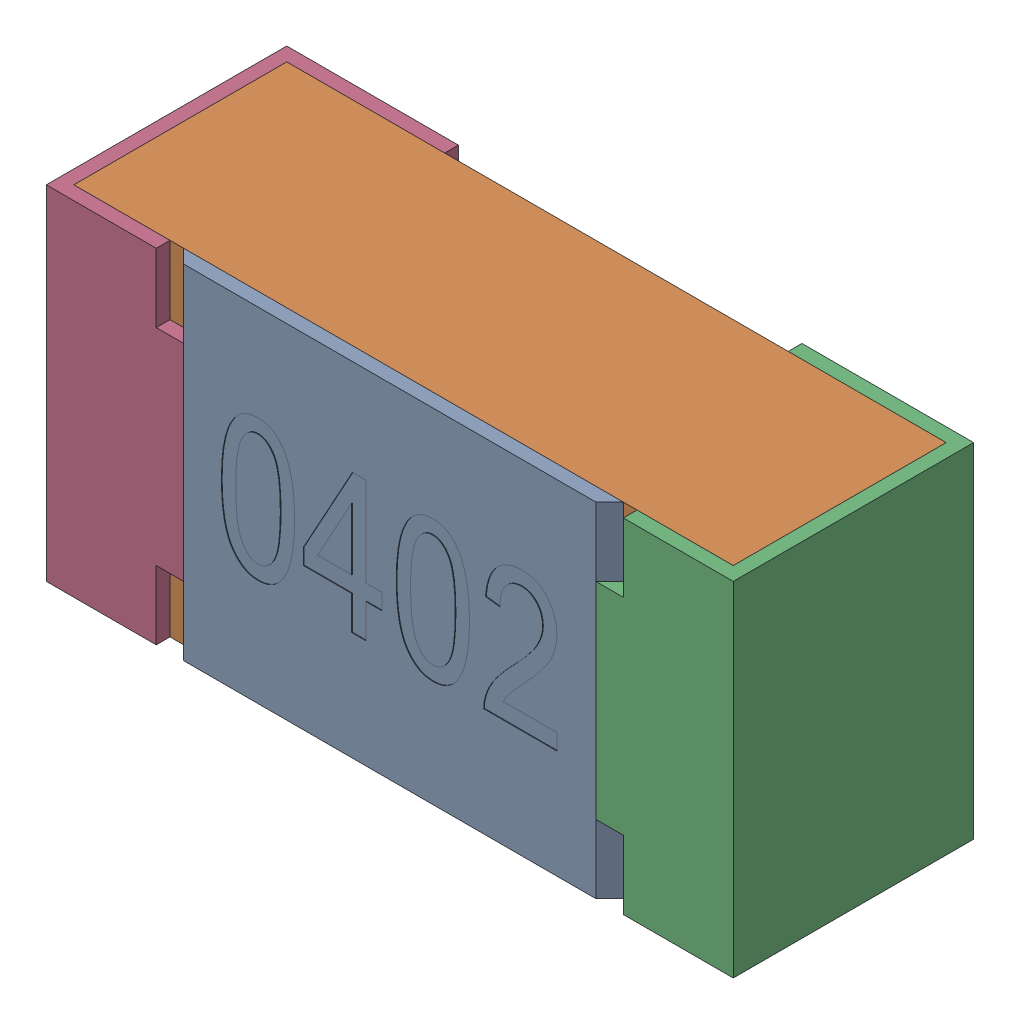
SolidWorks assembly R8, configuration Standard. Lengths in mm.
Overall size (1 0.5 0.35).
5 component instances, 4 part files, 0 mates.
Components (placement in the parent):
- R8-subassembly-1-1: R8-subassembly-1 [Standard] at (4.4001 -15.8 0) size (1 0.5 0.35)
  - User Library-R_0402-1: User Library-R_0402 [Standard] at origin size (0.64 0.5 0.02)
  - User Library-R_0402-1-1: User Library-R_0402-1 [Standard] at origin size (0.96 0.5 0.31)
  - User Library-R_0402-2-1: User Library-R_0402-2 [Standard] at origin size (0.25 0.5 0.35)
  - User Library-R_0402-3-1: User Library-R_0402-3 [Standard] at origin size (0.25 0.5 0.35)
